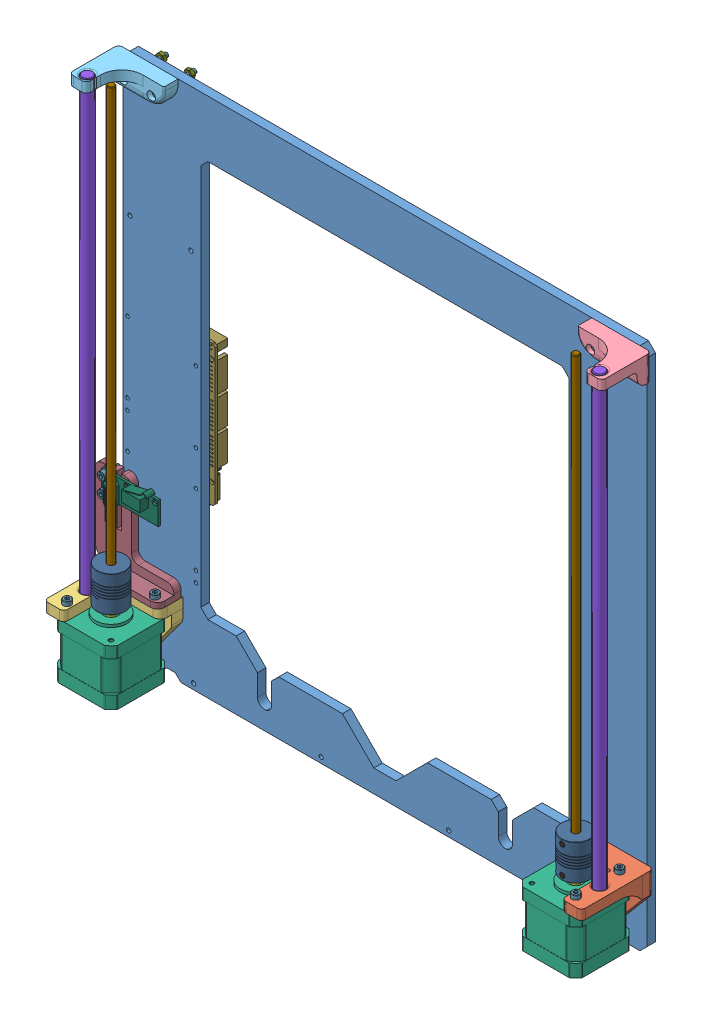
SolidWorks assembly Frame, configuration Default. Lengths in mm.
Overall size (452.86 372.2 75.95).
46 component instances, 16 part files, 38 mates.
Components (placement in the parent):
- main-frame-1: main-frame [Default] at origin size (370 370 6)
- z-axis-bottom-DX-01-1: z-axis-bottom-DX-01 [Default] at (386.3431 55 -54) x (0 0 1) z (0 -1 0) size (51 114 38.29)
- z-axis-bottom-SX-01-1: z-axis-bottom-SX-01 [Default] at (-13 55 -54) x (0 0 1) z (0 -1 0) size (52.5 47 38.29)
- z-axis-top-DX-o1-1: z-axis-top-DX-o1 [Default] at (350 360 6) x (-1 0 0) z (0 0 -1) size (42.04 39.81 40)
- z-axis-top-SX-o1-1: z-axis-top-SX-o1 [Default] at (100 360 6) x (-1 0 0) z (0 0 -1) size (126.01 39.81 40)
- Stepper_motor_NEMA17 39mm-1: Stepper_motor_NEMA17 39mm [Default] at (349 50 35.3) size (42 63.3 42)
  - Stator-1: Stator [Default] at origin size (42 41.1 42)
  - Rotor-1: Rotor [Default] x (0.508449 0 0.861092) z (-0.861092 0 0.508449) size (21 60.8 21)
- Stepper_motor_NEMA17 39mm-3: Stepper_motor_NEMA17 39mm [Default] at (21 50 35.3) size (42 63.3 42)
  - Stator-1: Stator [Default] at origin size (42 41.1 42)
  - Rotor-1: Rotor [Default] x (0.508449 0 0.861092) z (-0.861092 0 0.508449) size (21 60.8 21)
- 8x320-Sm_Rod-1: 8x320-Sm_Rod [Default] at (4.2 50.0879 35.3) x (-0.788009 0 0.615663) z (0 -1 0) size (8 8 320)
- M5x300-Th_Rod-1: M5x300-Th_Rod [Default] at (349 372.2 35.3) x (-0.54173 0 -0.840552) z (0 1 0) size (5 5 300)
- Acople Flexible5.5-1: Acople Flexible5.5 [Default] at (124.2696 67.5 -54.8152) x (0.964915 0 -0.262561) z (0 -1 0) size (20.86 20.77 25)
  - Acople Flexible 5.5-1: Acople Flexible 5.5 [Predeterminado] at (-123.3071 59.8391 -12.5) size (20.77 20.77 25)
  - socket set screw cone point_am-1: socket set screw cone point_am [B18.3.6M - M3 x 0.5 x 6 Hex Socket Cone Pt. SS --N] at (-133.7812 59.8391 9.5) x (1 0 0) z (0 0.199151 0.979969) size (6 3 3)
  - socket set screw cone point_am-3: socket set screw cone point_am [B18.3.6M - M3 x 0.5 x 6 Hex Socket Cone Pt. SS --N] at (-123.3071 49.5232 -9.5) x (0 1 0) z (-0.430549 0 0.902567) size (6 3 3)
  - socket set screw cone point_am-5: socket set screw cone point_am [B18.3.6M - M3 x 0.5 x 6 Hex Socket Cone Pt. SS --N] at (-123.3071 49.5452 9.5) x (0 1 0) z (0.224681 0 0.974432) size (6 3 3)
  - socket set screw cone point_am-7: socket set screw cone point_am [B18.3.6M - M3 x 0.5 x 6 Hex Socket Cone Pt. SS --N] at (-133.6418 59.8391 -9.5) x (1 0 0) z (0 -0.210117 0.977676) size (6 3 3)
- 8x320-Sm_Rod-3: 8x320-Sm_Rod [Default] at (365.8 50.0967 35.3) x (-0.483486 0 0.875352) z (0 -1 0) size (8 8 320)
- M5x300-Th_Rod-3: M5x300-Th_Rod [Default] at (21 72.2 35.3) x (0.854838 0 0.518895) z (0 -1 0) size (5 5 300)
- Acople Flexible5.5-3: Acople Flexible5.5 [Default] at (474.2049 67.5 91.0593) x (0.999461 0 -0.032825) z (0 1 0) size (20.86 20.77 25)
  - Acople Flexible 5.5-1: Acople Flexible 5.5 [Predeterminado] at (-123.3071 59.8391 -12.5) size (20.77 20.77 25)
  - socket set screw cone point_am-1: socket set screw cone point_am [B18.3.6M - M3 x 0.5 x 6 Hex Socket Cone Pt. SS --N] at (-133.7812 59.8391 9.5) x (1 0 0) z (0 0.199151 0.979969) size (6 3 3)
  - socket set screw cone point_am-3: socket set screw cone point_am [B18.3.6M - M3 x 0.5 x 6 Hex Socket Cone Pt. SS --N] at (-123.3071 49.5232 -9.5) x (0 1 0) z (-0.430549 0 0.902567) size (6 3 3)
  - socket set screw cone point_am-5: socket set screw cone point_am [B18.3.6M - M3 x 0.5 x 6 Hex Socket Cone Pt. SS --N] at (-123.3071 49.5452 9.5) x (0 1 0) z (0.224681 0 0.974432) size (6 3 3)
  - socket set screw cone point_am-7: socket set screw cone point_am [B18.3.6M - M3 x 0.5 x 6 Hex Socket Cone Pt. SS --N] at (-133.6418 59.8391 -9.5) x (1 0 0) z (0 -0.210117 0.977676) size (6 3 3)
- ArduinoMega-1: ArduinoMega [Default] at (27.4632 161.2114 -6.651) x (0 -1 0) z (0 0 1) size (107.95 53.42 12.95)
- end stop Z- support-1: end stop Z- support [Default] at (17.7233 80 7.3) size (53.55 60 16.5)
- Socket head cap screw-1: Socket head cap screw [M3x10] at (340 360 13) x (0 0 -1) z (1 0 0) size (13 5.5 5.5)
- Socket head cap screw-3: Socket head cap screw [M3x10] at (360 360 13) x (0 0 -1) z (1 0 0) size (13 5.5 5.5)
- Socket head cap screw-5: Socket head cap screw [M3x25] at (30 360 13) x (0 0 -1) z (1 0 0) size (28 5.5 5.5)
- Socket head cap screw-7: Socket head cap screw [M3x10] at (364.5 58 50.8) x (0 -1 0) z (-0.290933 0 0.956743) size (13 5.5 5.5)
- Socket head cap screw-9: Socket head cap screw [M3x10] at (5.5 58 50.8) x (0 -1 0) z (0.997858 0 0.065425) size (13 5.5 5.5)
- Socket head cap screw-11: Socket head cap screw [M3x14] at (5.9313 62 19.3515) x (0 -1 0) z (0.959191 0 0.28276) size (17 5.5 5.5)
- Socket head cap screw-13: Socket head cap screw [M3x14] at (36.5086 62 19.8015) x (0 -1 0) z (-0.958116 0 -0.286382) size (17 5.5 5.5)
- Socket head cap screw-15: Socket head cap screw [M3x10] at (364.5 58 19.8) x (0 -1 0) z (0 0 1) size (13 5.5 5.5)
- Socket head cap screw-17: Socket head cap screw [M3x10] at (333.5 58 19.8) x (0 -1 0) z (-0.842603 0 -0.538535) size (13 5.5 5.5)
- Socket head cap screw-19: Socket head cap screw [M3x25] at (10 360 13) x (0 0 -1) z (1 0 0) size (28 5.5 5.5)
- Mech endstop-1: Mech endstop [Default] at (12.8486 105.0903 12.3134) size (40 21.02 12.37)
- Socket head cap screw-20: Socket head cap screw [M3x10] at (-4.6514 110.5903 16.9134) x (0 0 -1) z (1 0 0) size (13 5.5 5.5)
- Hex nut-1: Hex nut [M3 Hex Nut] at (-4.6514 99.5903 9.2201) x (0.999995 -0.003142 0) z (0 0 1) size (5.5 6.35 2.4)
- Socket head cap screw-22: Socket head cap screw [M3x10] at (-4.6514 99.5903 16.9134) x (0 0 -1) z (1 -0.000192 0) size (13 5.5 5.5)
- Hex nut-3: Hex nut [M3 Hex Nut] at (10 360 -10) x (-0.188876 -0.982001 0) z (0 0 1) size (5.5 6.35 2.4)
- Hex nut-5: Hex nut [M3 Hex Nut] at (30 360 -10) x (0.958903 -0.283734 0) z (0 0 1) size (5.5 6.35 2.4)
- Hex nut-7: Hex nut [M3 Hex Nut] at (-4.6514 110.5903 9.2248) x (0.958903 -0.283734 0) z (0 0 1) size (5.5 6.35 2.4)
Mates (geometry in assembly coordinates):
- Concentric15: concentric aligned: cylinder of Stepper_motor_NEMA17 39mm-3/Rotor-1 through (21 72.2 35.3) axis (0 1 0) radius 2.5; cylinder of Acople Flexible5.5-1/Acople Flexible 5.5-1 through (21 55 35.3) axis (0 1 0) radius 2.5
- Distance1: distance = 5 mm anti-aligned: plane of Acople Flexible5.5-1/Acople Flexible 5.5-1 through (21 55 35.3) normal (0 -1 0); plane of Stepper_motor_NEMA17 39mm-3/Stator-1 through (26 50 35.3) normal (0 1 0)
- Concentric16: concentric anti-aligned: cylinder of Stepper_motor_NEMA17 39mm-1/Rotor-1 through (349 72.2 35.3) axis (0 1 0) radius 2.5; cylinder of Acople Flexible5.5-3/Acople Flexible 5.5-1 through (349 80 35.3) axis (0 -1 0) radius 2.5
- Distance2: distance = 5 mm anti-aligned: plane of Acople Flexible5.5-3/Acople Flexible 5.5-1 through (349 55 35.3) normal (0 -1 0); plane of Stepper_motor_NEMA17 39mm-1/Stator-1 through (354 50 35.3) normal (0 1 0)
- Concentric17: concentric anti-aligned: cylinder of Acople Flexible5.5-1/Acople Flexible 5.5-1 through (21 55 35.3) axis (0 1 0) radius 2.5; cylinder of M5x300-Th_Rod-3 through (21 372.2 35.3) axis (0 -1 0) radius 2.5
- Coincident9: coincident anti-aligned: plane of Stepper_motor_NEMA17 39mm-3/Rotor-1 through (22.2711 72.2 37.4527) normal (0 1 0); plane of M5x300-Th_Rod-3 through (21 72.2 35.3) normal (0 -1 0)
- Concentric18: concentric anti-aligned: cylinder of M5x300-Th_Rod-1 through (349 72.2 35.3) axis (0 1 0) radius 2.5; cylinder of Acople Flexible5.5-3/Acople Flexible 5.5-1 through (349 80 35.3) axis (0 -1 0) radius 2.5
- Coincident10: coincident anti-aligned: plane of Stepper_motor_NEMA17 39mm-1/Rotor-1 through (350.2711 72.2 37.4527) normal (0 1 0); plane of M5x300-Th_Rod-1 through (349 72.2 35.3) normal (0 -1 0)
- Concentric36: concentric anti-aligned: cylinder of Mech endstop-1 through (-4.6514 99.5903 13.9134) axis (0 0 -1) radius 1.75; cylinder of Socket head cap screw-22 through (-4.6514 99.5903 48.6634) axis (0 0 1) radius 1.5
- Concentric37: concentric anti-aligned: cylinder of Mech endstop-1 through (-4.6514 110.5903 13.9134) axis (0 0 -1) radius 1.75; cylinder of Socket head cap screw-20 through (-4.6514 110.5903 48.6634) axis (0 0 1) radius 1.5
- Coincident23: coincident anti-aligned: plane of Mech endstop-1 through (12.8486 105.0903 13.9134) normal (0 0 1); plane of Socket head cap screw-20 through (-4.6514 113.3403 13.9134) normal (0 0 -1)
- Coincident24: coincident anti-aligned: plane of Mech endstop-1 through (12.8486 105.0903 13.9134) normal (0 0 1); plane of Socket head cap screw-22 through (-4.6509 102.3403 13.9134) normal (0 0 -1)
- Concentric40: concentric aligned: cylinder of Hex nut-1 through (-4.6514 99.5903 6.8201) axis (0 0 1) radius 1.25; cylinder of Socket head cap screw-22 through (-4.6514 99.5903 48.6634) axis (0 0 1) radius 1.5
- Coincident25: coincident anti-aligned: plane of main-frame-1 through (0 0 6) normal (0 0 1); plane of z-axis-top-DX-o1-1 through (350 360 6) normal (0 0 -1)
- Concentric42: concentric aligned: cylinder of main-frame-1 through (340 360 6) axis (0 0 -1) radius 1.5; cylinder of z-axis-top-DX-o1-1 through (340 360 46) axis (0 0 -1) radius 1.5
- Concentric43: concentric aligned: cylinder of main-frame-1 through (360 360 6) axis (0 0 -1) radius 1.5; cylinder of z-axis-top-DX-o1-1 through (360 360 46) axis (0 0 -1) radius 1.5
- Coincident26: coincident anti-aligned: plane of main-frame-1 through (0 0 6) normal (0 0 1); plane of z-axis-top-SX-o1-1 through (20 360 6) normal (0 0 -1)
- Concentric44: concentric aligned: cylinder of main-frame-1 through (30 360 6) axis (0 0 -1) radius 1.5; cylinder of z-axis-top-SX-o1-1 through (30 360 46) axis (0 0 -1) radius 1.5
- Concentric45: concentric aligned: cylinder of main-frame-1 through (10 360 6) axis (0 0 -1) radius 1.5; cylinder of z-axis-top-SX-o1-1 through (10 360 46) axis (0 0 -1) radius 1.5
- Concentric46: concentric aligned: cylinder of main-frame-1 through (30 40 6) axis (0 0 -1) radius 1.5; cylinder of z-axis-bottom-SX-01-1 through (30 40 14) axis (0 0 -1) radius 1.75
- Concentric47: concentric aligned: cylinder of main-frame-1 through (10 40 6) axis (0 0 -1) radius 1.5; cylinder of z-axis-bottom-SX-01-1 through (10 40 14) axis (0 0 -1) radius 1.75
- Coincident27: coincident anti-aligned: plane of main-frame-1 through (0 0 6) normal (0 0 1); plane of z-axis-bottom-SX-01-1 through (-13 55 6) normal (0 0 -1)
- Concentric51: concentric aligned: cylinder of main-frame-1 through (3.2951 207.16 6) axis (0 0 -1) radius 1.25; cylinder of ArduinoMega-1 through (3.2951 207.16 -4.999) axis (0 0 -1) radius 1.5621
- Parallel3: parallel aligned: plane of main-frame-1 through (0 0 6) normal (-1 0 0); plane of ArduinoMega-1 through (0.7551 212.0114 -5) normal (-1 0 0)
- Distance3: distance = 5 mm anti-aligned: plane of ArduinoMega-1 through (0.7551 110.4114 -5) normal (0 0 1); plane of main-frame-1 through (0 0 0) normal (0 0 -1)
- Concentric52: concentric aligned: cylinder of Socket head cap screw-5 through (30 360 44.75) axis (0 0 1) radius 1.5; cylinder of Hex nut-5 through (30 360 -12.4) axis (0 0 1) radius 1.25
- Distance4: distance = 10 mm anti-aligned: plane of main-frame-1 through (0 0 0) normal (0 0 -1); plane of Hex nut-5 through (30.901 363.0449 -10) normal (0 0 1)
- Concentric53: concentric aligned: cylinder of Socket head cap screw-19 through (10 360 44.75) axis (0 0 1) radius 1.5; cylinder of Hex nut-3 through (10 360 -12.4) axis (0 0 1) radius 1.25
- Distance5: distance = 10 mm anti-aligned: plane of Hex nut-3 through (13.1183 359.4002 -10) normal (0 0 1); plane of main-frame-1 through (0 0 0) normal (0 0 -1)
- Concentric55: concentric aligned: cylinder of Stepper_motor_NEMA17 39mm-3/Stator-1 through (5.5 42 50.8) axis (0 1 0) radius 1.25; cylinder of Socket head cap screw-9 through (5.5 89.75 50.8) axis (0 1 0) radius 1.5
- Parallel4: parallel aligned: cylinder of Stepper_motor_NEMA17 39mm-3/Stator-1 through (36.5 42 19.8) axis (0 1 0) radius 1.25; cylinder of Socket head cap screw-13 through (36.5086 93.75 19.8015) axis (0 1 0) radius 1.5
- Coincident29: coincident anti-aligned: plane of z-axis-bottom-SX-01-1 through (-13 48 -54) normal (0 -1 0); plane of Stepper_motor_NEMA17 39mm-3/Stator-1 through (32 48 35.3) normal (0 1 0)
- Concentric57: concentric aligned: cylinder of main-frame-1 through (360 40 6) axis (0 0 -1) radius 1.5; cylinder of z-axis-bottom-DX-01-1 through (360 40 14) axis (0 0 -1) radius 1.75
- Concentric58: concentric aligned: cylinder of main-frame-1 through (350 20 6) axis (0 0 -1) radius 1.5; cylinder of z-axis-bottom-DX-01-1 through (350 20 14) axis (0 0 -1) radius 1.75
- Coincident30: coincident anti-aligned: plane of main-frame-1 through (0 0 6) normal (0 0 1); plane of z-axis-bottom-DX-01-1 through (383 55 6) normal (0 0 -1)
- Concentric59: concentric aligned: cylinder of Stepper_motor_NEMA17 39mm-1/Stator-1 through (364.5 42 50.8) axis (0 1 0) radius 1.25; cylinder of Socket head cap screw-7 through (364.5 89.75 50.8) axis (0 1 0) radius 1.5
- Concentric60: concentric aligned: cylinder of Stepper_motor_NEMA17 39mm-1/Stator-1 through (333.5 42 19.8) axis (0 1 0) radius 1.25; cylinder of Socket head cap screw-17 through (333.5 89.75 19.8) axis (0 1 0) radius 1.5
- Coincident31: coincident anti-aligned: plane of z-axis-bottom-DX-01-1 through (383 48 -54) normal (0 -1 0); plane of Stepper_motor_NEMA17 39mm-1/Stator-1 through (360 48 35.3) normal (0 1 0)
